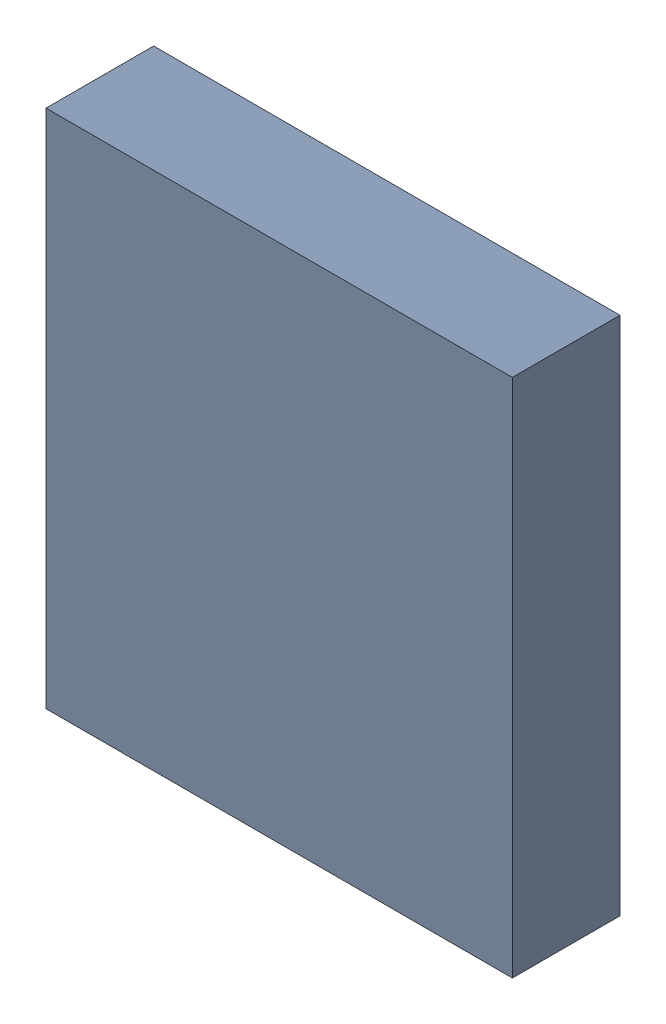
SolidWorks assembly U12.step, configuration Default. Lengths in mm.
Overall size (2.6 2.9 0.6).
2 component instances, 1 part files, 0 mates.
Components (placement in the parent):
- 6401096528.step-1: 6401096528.step [Default] at (12.3444 -5.4864 0) size (2.6 2.9 0.6)
  - Extruded (25).step-1: Extruded (25).step [Default] at origin size (2.6 2.9 0.6)
